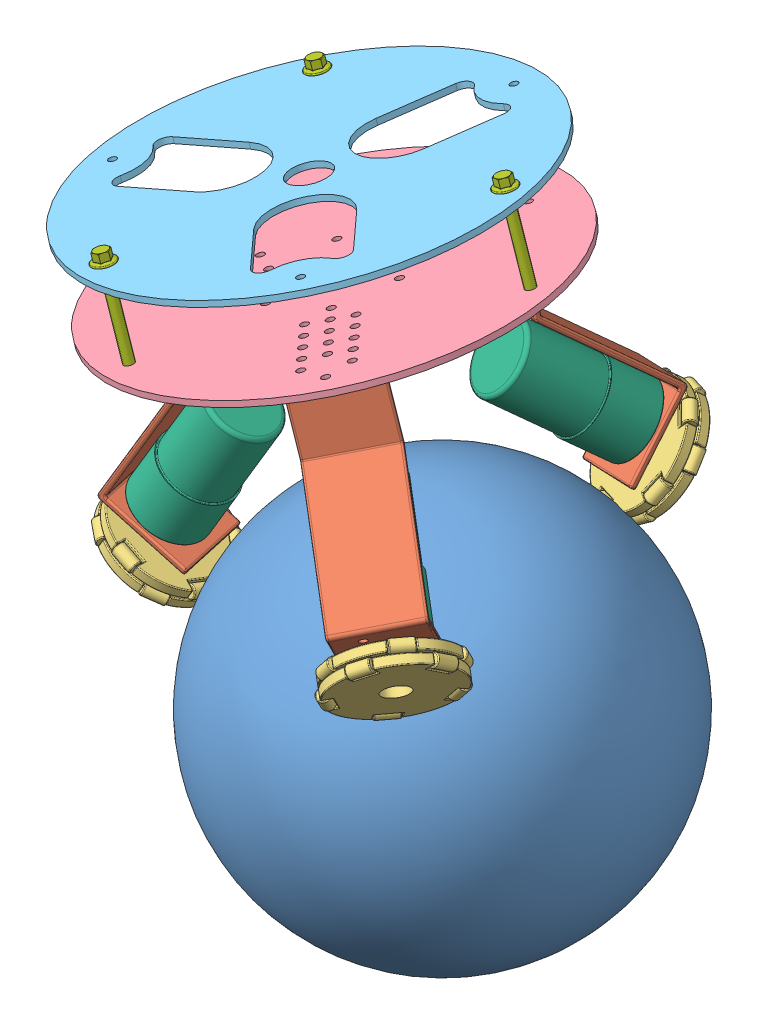
SolidWorks assembly BallBot2, configuration Default. Lengths in mm.
Overall size (357.87 430.69 302.88).
18 component instances, 7 part files, 42 mates.
Components (placement in the parent):
- Ball64cm-1: Ball64cm [Default] at (184.3002 -230.0482 12.6376) x (0.179804 0.35451 -0.917602) z (-0.783599 -0.512292 -0.351467) size (203.72 203.72 203.72)
- FixMotorPart-1: FixMotorPart [Default] at (191.7275 -139.1469 -81.9144) x (-0.009939 0.75847 -0.651632) z (0.377377 -0.60063 -0.704861) size (71.58 40 121.2)
- HaftOmniWheel-1: HaftOmniWheel [Default] at (66.5214 -196.2001 43.2536) x (-0.354156 0.03791 -0.934418) z (0.465262 0.873889 -0.140886) size (60.44 59.16 6.4)
- MainPartBot-2: MainPartBot [Default] at (136.2631 -50.886 21.6956) x (-0.688012 -0.223115 0.690549) z (-0.273874 0.961029 0.037639) size (203.72 203.72 3)
- MainPartTop-1: MainPartTop [Default] at (124.4866 -9.5618 23.314) x (-0.688012 -0.223115 0.690549) z (-0.273874 0.961029 0.037639) size (203.72 203.72 3)
- Motor-1: Motor [Default] at (235.5656 -130.9879 94.5403) x (-0.281543 -0.794969 -0.537361) z (-0.668859 0.564131 -0.484132) size (37 37 81)
- FixMotorPart-2: FixMotorPart [Default] at (234.5738 -133.7816 92.8617) x (0.281543 0.794969 0.537361) z (0.668859 -0.564131 0.484132) size (71.58 40 121.2)
- HaftOmniWheel-2: HaftOmniWheel [Default] at (69.313 -190.9567 42.4083) x (0.190315 -0.254197 -0.948243) z (0.465262 0.873889 -0.140886) size (60.44 59.16 6.4)
- Motor-2: Motor [Default] at (191.5202 -136.5435 -84.1019) x (0.009939 -0.75847 0.651632) z (-0.377377 0.60063 0.704861) size (37 37 81)
- FixMotorPart-3: FixMotorPart [Default] at (67.8637 -179.3146 42.4062) x (-0.852578 0.485211 0.194115) z (-0.465262 -0.873889 0.140886) size (71.58 40 121.2)
- HaftOmniWheel-3: HaftOmniWheel [Default] at (195.381 -150.0742 -84.1247) x (-0.407148 -0.791242 0.456253) z (0.377377 -0.60063 -0.704861) size (60.44 59.16 6.4)
- Motor-3: Motor [Default] at (65.0446 -177.5721 43.1948) x (0.852578 -0.485211 -0.194115) z (0.465262 0.873889 -0.140886) size (37 37 81)
- HaftOmniWheel-4: HaftOmniWheel [Default] at (197.6453 -153.678 -88.3538) x (-0.818283 -0.572648 0.049865) z (0.377377 -0.60063 -0.704861) size (60.44 59.16 6.4)
- HaftOmniWheel-5: HaftOmniWheel [Default] at (238.9899 -144.6135 93.7618) x (-0.184258 0.50512 0.84315) z (-0.668859 0.564131 -0.484132) size (60.44 59.16 6.4)
- HaftOmniWheel-6: HaftOmniWheel [Default] at (243.003 -147.9983 96.6666) x (-0.572386 0.024736 0.819611) z (-0.668859 0.564131 -0.484132) size (60.44 59.16 6.4)
- hex flange bolt small_iso-2: hex flange bolt small_iso [ISO 4162 - M5 x 50 x 16-N] at (61.6206 -15.8913 -41.366) x (0.273874 -0.961029 -0.037639) z (0.875536 0.265324 -0.403783) size (55.6 11.4 11.4)
- hex flange bolt small_iso-3: hex flange bolt small_iso [ISO 4162 - M5 x 50 x 16-N] at (98.7202 -11.2457 109.9682) x (0.273874 -0.961029 -0.037639) z (-0.800099 -0.249379 0.545575) size (55.6 11.4 11.4)
- hex flange bolt small_iso-4: hex flange bolt small_iso [ISO 4162 - M5 x 50 x 16-N] at (206.0255 23.3423 2.3147) x (0.273874 -0.961029 -0.037639) z (-0.76923 -0.195388 -0.608366) size (55.6 11.4 11.4)
Mates (geometry in assembly coordinates):
- Concentric1: concentric aligned: cylinder of MainPartBot-2 through (135.4415 -48.003 21.8085) axis (0.273874 -0.961029 -0.037639) radius 10; cylinder of MainPartTop-1 through (123.6649 -6.6787 23.427) axis (0.273874 -0.961029 -0.037639) radius 10
- Concentric2: concentric aligned: cylinder of MainPartBot-2 through (74.9583 -62.6934 -43.199) axis (0.273874 -0.961029 -0.037639) radius 2; cylinder of MainPartTop-1 through (63.1817 -21.3692 -41.5805) axis (0.273874 -0.961029 -0.037639) radius 2
- Distance1: distance = 1 mm anti-aligned: plane of HaftOmniWheel-1 through (67.6845 -194.0153 42.9014) normal (0.465262 0.873889 -0.140886); plane of HaftOmniWheel-2 through (68.1498 -193.1415 42.7605) normal (-0.465262 -0.873889 0.140886)
- Concentric3: concentric aligned: cylinder of HaftOmniWheel-1 through (67.6845 -194.0153 42.9014) axis (-0.465262 -0.873889 0.140886) radius 6.5; cylinder of HaftOmniWheel-2 through (70.4761 -188.772 42.0561) axis (-0.465262 -0.873889 0.140886) radius 6.5
- Angle1: planar angle = 0.628319 rad anti-aligned: plane of HaftOmniWheel-2 through (88.8298 -199.4347 54.2738) normal (-0.190315 0.254197 0.948243); plane of HaftOmniWheel-1 through (85.9248 -203.6276 61.2599) normal (0.662092 -0.44921 -0.599871)
- Concentric4: concentric aligned: cylinder of HaftOmniWheel-3 through (196.3245 -151.5758 -85.8868) axis (-0.377377 0.60063 0.704861) radius 6.5; cylinder of HaftOmniWheel-4 through (198.5887 -155.1796 -90.116) axis (-0.377377 0.60063 0.704861) radius 6.5
- Distance2: distance = 1 mm anti-aligned: plane of HaftOmniWheel-3 through (196.3245 -151.5758 -85.8868) normal (0.377377 -0.60063 -0.704861); plane of HaftOmniWheel-4 through (196.7018 -152.1764 -86.5917) normal (-0.377377 0.60063 0.704861)
- Angle2: planar angle = 0.628319 rad anti-aligned: plane of HaftOmniWheel-3 through (171.6447 -163.9176 -85.0366) normal (0.159504 -0.707608 0.688367); plane of HaftOmniWheel-4 through (176.6952 -171.1069 -84.7187) normal (-0.66523 0.353692 -0.657549)
- Concentric5: concentric aligned: cylinder of HaftOmniWheel-5 through (237.3177 -143.2031 92.5514) axis (0.668859 -0.564131 0.484132) radius 6.5; cylinder of HaftOmniWheel-6 through (241.3309 -146.5879 95.4562) axis (0.668859 -0.564131 0.484132) radius 6.5
- Distance3: distance = 1 mm anti-aligned: plane of HaftOmniWheel-5 through (240.662 -146.0238 94.9721) normal (0.668859 -0.564131 0.484132); plane of HaftOmniWheel-6 through (241.3309 -146.5879 95.4562) normal (-0.668859 0.564131 -0.484132)
- Angle3: planar angle = 0.628319 rad anti-aligned: plane of HaftOmniWheel-6 through (240.2858 -132.1073 118.9372) normal (-0.741882 -0.465096 0.483008); plane of HaftOmniWheel-5 through (231.6447 -132.9198 117.5355) normal (0.628004 0.777277 0.038087)
- Distance4: distance = 40 mm anti-aligned: plane of MainPartTop-1 through (124.4866 -9.5618 23.314) normal (0.273874 -0.961029 -0.037639); plane of MainPartBot-2 through (135.4415 -48.003 21.8085) normal (-0.273874 0.961029 0.037639)
- Concentric6: concentric aligned: cylinder of FixMotorPart-1 through (192.9281 -146.1701 -79.5431) axis (-0.377377 0.60063 0.704861) radius 6.207; cylinder of Motor-2 through (194.0225 -147.9119 -81.5872) axis (-0.377377 0.60063 0.704861) radius 6.207
- Concentric7: concentric anti-aligned: cylinder of FixMotorPart-1 through (207.1709 -136.2567 -80.3651) axis (-0.377377 0.60063 0.704861) radius 2; cylinder of Motor-2 through (204.8688 -132.5928 -76.0654) axis (0.377377 -0.60063 -0.704861) radius 2
- Distance5: distance = 0.1 mm anti-aligned: plane of Motor-2 through (191.7237 -139.0205 -81.8822) normal (0.377377 -0.60063 -0.704861); plane of FixMotorPart-1 through (191.7275 -139.1469 -81.9144) normal (-0.377377 0.60063 0.704861)
- Concentric8: concentric aligned: cylinder of Motor-1 through (236.582 -142.5826 92.0189) axis (-0.668859 0.564131 -0.484132) radius 6.207; cylinder of FixMotorPart-2 through (234.6423 -140.9466 90.6149) axis (-0.668859 0.564131 -0.484132) radius 6.207
- Concentric9: concentric anti-aligned: cylinder of Motor-1 through (222.1494 -134.6654 102.5938) axis (0.668859 -0.564131 0.484132) radius 2; cylinder of FixMotorPart-2 through (226.2295 -138.1066 105.547) axis (-0.668859 0.564131 -0.484132) radius 2
- Distance6: distance = 0.1 mm anti-aligned: plane of Motor-1 through (234.5023 -133.674 92.8794) normal (0.668859 -0.564131 0.484132); plane of FixMotorPart-2 through (234.5738 -133.7816 92.8617) normal (-0.668859 0.564131 -0.484132)
- Concentric10: concentric aligned: cylinder of FixMotorPart-3 through (72.3372 -185.2765 41.4925) axis (0.465262 0.873889 -0.140886) radius 6.207; cylinder of Motor-3 through (70.9879 -187.8107 41.9011) axis (0.465262 0.873889 -0.140886) radius 6.207
- Concentric11: concentric anti-aligned: cylinder of FixMotorPart-3 through (61.9098 -181.8978 28.0142) axis (0.465262 0.873889 -0.140886) radius 2; cylinder of Motor-3 through (64.7479 -176.5671 27.1548) axis (-0.465262 -0.873889 0.140886) radius 2
- Distance7: distance = 0.1 mm anti-aligned: plane of Motor-3 through (67.8375 -179.1919 42.3703) normal (-0.465262 -0.873889 0.140886); plane of FixMotorPart-3 through (67.8637 -179.3146 42.4062) normal (0.465262 0.873889 -0.140886)
- Distance8: distance = 0.1 mm anti-aligned: plane of FixMotorPart-2 through (206.1427 -34.0161 96.769) normal (-0.273874 0.961029 0.037639); plane of MainPartBot-2 through (136.2631 -50.886 21.6956) normal (0.273874 -0.961029 -0.037639)
- Concentric16: concentric anti-aligned: cylinder of MainPartBot-2 through (169.0433 -39.8416 57.9238) axis (0.273874 -0.961029 -0.037639) radius 2; cylinder of FixMotorPart-2 through (170.7139 -45.7038 57.6942) axis (-0.273874 0.961029 0.037639) radius 2
- Concentric17: concentric anti-aligned: cylinder of MainPartBot-2 through (168.8835 -40.4404 72.0523) axis (0.273874 -0.961029 -0.037639) radius 2; cylinder of FixMotorPart-2 through (170.5542 -46.3027 71.8227) axis (-0.273874 0.961029 0.037639) radius 2
- Concentric18: concentric anti-aligned: cylinder of MainPartBot-2 through (88.8488 -61.7448 33.6525) axis (0.273874 -0.961029 -0.037639) radius 2; cylinder of FixMotorPart-3 through (90.5194 -67.6071 33.423) axis (-0.273874 0.961029 0.037639) radius 2
- Concentric20: concentric anti-aligned: cylinder of MainPartBot-2 through (77.1503 -64.7912 26.3133) axis (0.273874 -0.961029 -0.037639) radius 2; cylinder of FixMotorPart-3 through (78.821 -70.6535 26.0837) axis (-0.273874 0.961029 0.037639) radius 2
- Distance9: distance = 0.1 mm anti-aligned: plane of MainPartBot-2 through (136.2631 -50.886 21.6956) normal (0.273874 -0.961029 -0.037639); plane of FixMotorPart-3 through (39.4326 -79.549 46.3135) normal (-0.273874 0.961029 0.037639)
- Concentric21: concentric anti-aligned: cylinder of FixMotorPart-1 through (150.1031 -48.2848 -26.3804) axis (-0.273874 0.961029 0.037639) radius 2; cylinder of MainPartBot-2 through (148.4324 -42.4225 -26.1508) axis (0.273874 -0.961029 -0.037639) radius 2
- Concentric22: concentric anti-aligned: cylinder of FixMotorPart-1 through (161.9613 -44.6395 -33.1696) axis (-0.273874 0.961029 0.037639) radius 2; cylinder of MainPartBot-2 through (160.2907 -38.7772 -32.9401) axis (0.273874 -0.961029 -0.037639) radius 2
- Distance10: distance = 0.1 mm anti-aligned: plane of MainPartBot-2 through (136.2631 -50.886 21.6956) normal (0.273874 -0.961029 -0.037639); plane of FixMotorPart-1 through (163.2963 -39.3813 -78.007) normal (-0.273874 0.961029 0.037639)
- Concentric23: concentric anti-aligned: cylinder of Motor-1 through (236.582 -142.5826 92.0189) axis (-0.668859 0.564131 -0.484132) radius 6.207; cylinder of HaftOmniWheel-5 through (237.3177 -143.2031 92.5514) axis (0.668859 -0.564131 0.484132) radius 6.5
- Distance11: distance = 4 mm anti-aligned: plane of HaftOmniWheel-5 through (237.3177 -143.2031 92.5514) normal (-0.668859 0.564131 -0.484132); plane of FixMotorPart-2 through (236.5804 -135.474 94.3141) normal (0.668859 -0.564131 0.484132)
- Concentric24: concentric anti-aligned: cylinder of HaftOmniWheel-2 through (70.4761 -188.772 42.0561) axis (-0.465262 -0.873889 0.140886) radius 6.5; cylinder of Motor-3 through (70.9879 -187.8107 41.9011) axis (0.465262 0.873889 -0.140886) radius 6.207
- Distance12: distance = 4 mm anti-aligned: plane of HaftOmniWheel-2 through (70.4761 -188.772 42.0561) normal (0.465262 0.873889 -0.140886); plane of FixMotorPart-3 through (66.468 -181.9362 42.8288) normal (-0.465262 -0.873889 0.140886)
- Concentric25: concentric aligned: cylinder of Motor-2 through (194.0225 -147.9119 -81.5872) axis (-0.377377 0.60063 0.704861) radius 6.207; cylinder of HaftOmniWheel-4 through (198.5887 -155.1796 -90.116) axis (-0.377377 0.60063 0.704861) radius 6.5
- Distance13: distance = 4 mm anti-aligned: plane of HaftOmniWheel-3 through (194.4376 -148.5726 -82.3625) normal (-0.377377 0.60063 0.704861); plane of FixMotorPart-1 through (192.8597 -140.9488 -84.0289) normal (0.377377 -0.60063 -0.704861)
- Concentric26: concentric anti-aligned: cylinder of MainPartTop-1 through (207.5318 18.0566 2.1077) axis (0.273874 -0.961029 -0.037639) radius 2; cylinder of hex flange bolt small_iso-4 through (206.0255 23.3423 2.3147) axis (-0.273874 0.961029 0.037639) radius 2.5
- Concentric27: concentric anti-aligned: cylinder of MainPartTop-1 through (100.2813 -16.7236 109.7537) axis (0.273874 -0.961029 -0.037639) radius 2; cylinder of hex flange bolt small_iso-3 through (98.7202 -11.2457 109.9682) axis (-0.273874 0.961029 0.037639) radius 2.5
- Distance14: distance = 0.1 mm anti-aligned: plane of hex flange bolt small_iso-4 through (205.226 17.1701 5.3078) normal (0.273874 -0.961029 -0.037639); plane of MainPartTop-1 through (123.6649 -6.6787 23.427) normal (-0.273874 0.961029 0.037639)
- Distance15: distance = 0.1 mm anti-aligned: plane of hex flange bolt small_iso-3 through (102.4108 -16.1453 113.141) normal (0.273874 -0.961029 -0.037639); plane of MainPartTop-1 through (123.6649 -6.6787 23.427) normal (-0.273874 0.961029 0.037639)
- Concentric28: concentric anti-aligned: cylinder of MainPartTop-1 through (63.1817 -21.3692 -41.5805) axis (0.273874 -0.961029 -0.037639) radius 2; cylinder of hex flange bolt small_iso-2 through (61.6206 -15.8913 -41.366) axis (-0.273874 0.961029 0.037639) radius 2.5
- Distance16: distance = 0.1 mm anti-aligned: plane of hex flange bolt small_iso-2 through (61.5457 -21.5868 -45.2709) normal (0.273874 -0.961029 -0.037639); plane of MainPartTop-1 through (123.6649 -6.6787 23.427) normal (-0.273874 0.961029 0.037639)
